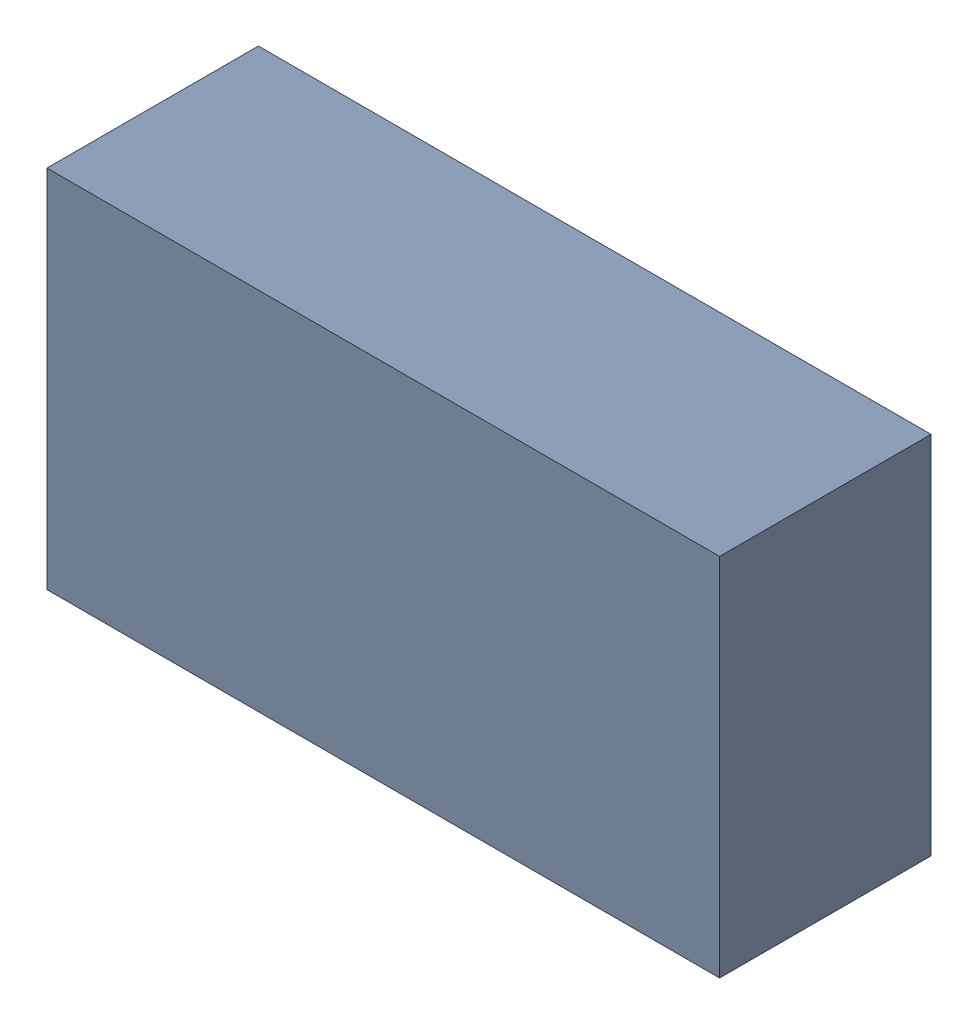
SolidWorks assembly L4_TDA4, configuration Standard. Lengths in mm.
Overall size (1.75 0.95 0.55).
2 component instances, 1 part files, 0 mates.
Components (placement in the parent):
- 885542648-1: 885542648 [Standard] at (0.18 -59.19 0) size (1.75 0.95 0.55)
  - Extruded_19-1: Extruded_19 [Standard] at origin size (1.75 0.95 0.55)
